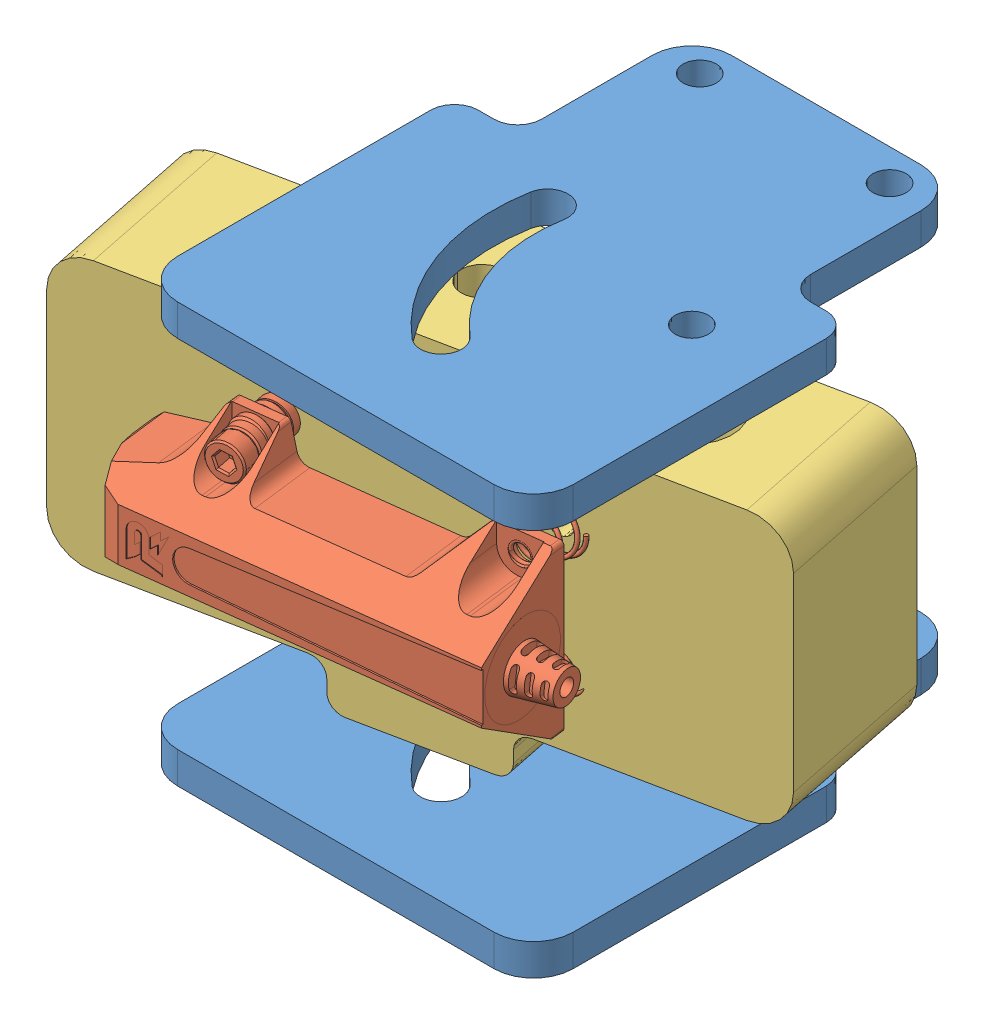
SolidWorks assembly 激光瞄准, configuration 默认. Lengths in mm.
Overall size (82.38 53 68.83).
4 component instances, 3 part files, 8 mates.
Components (placement in the parent):
- 21RM_飞镖.02.01.0048(激光瞄准旋转板)-1: 21RM_飞镖.02.01.0048(激光瞄准旋转板) [默认] at (10.6567 7.7365 63) size (50 4 62)
- 21RM_飞镖.02.01.0048(激光瞄准旋转板)-2: 21RM_飞镖.02.01.0048(激光瞄准旋转板) [默认] at (10.6567 -41.2635 63) size (50 4 62)
- 21RM_飞镖.02.01.0045(RoboMaster激光瞄准)-1: 21RM_飞镖.02.01.0045(RoboMaster激光瞄准) [默认] at (-50.7503 5.6982 100.4699) x (0 -1 0) z (-0.979741 0 0.200267) size (22.28 20.81 51.36)
- 21RM_飞镖.02.01.0046(激光瞄准固定板)-1: 21RM_飞镖.02.01.0046(激光瞄准固定板) [默认] at (-13.3901 -14.7635 57.7086) x (0 -1 0) z (-0.979741 0 0.200267) size (45 20 80)
Mates (geometry in assembly coordinates):
- 同心1: concentric aligned: cylinder of 21RM_飞镖.02.01.0048(激光瞄准旋转板)-1 through (10.6567 11.7365 63) axis (0 -1 0) radius 2.1; cylinder of 21RM_飞镖.02.01.0048(激光瞄准旋转板)-2 through (10.6567 -37.2635 63) axis (0 -1 0) radius 2.1
- 同心2: concentric aligned: circle of 21RM_飞镖.02.01.0045(RoboMaster激光瞄准)-1; cylinder of 21RM_飞镖.02.01.0046(激光瞄准固定板)-1 through (-24.0809 -22.7635 80.3074) axis (-0.200267 0 -0.979741) radius 1.6
- 同心5: concentric anti-aligned: cylinder of 21RM_飞镖.02.01.0045(RoboMaster激光瞄准)-1 through (-24.768 -6.7635 76.9458) axis (0.200267 0 0.979741) radius 1.25; cylinder of 21RM_飞镖.02.01.0046(激光瞄准固定板)-1 through (-24.0809 -6.7635 80.3074) axis (-0.200267 0 -0.979741) radius 1.6
- 重合3: coincident anti-aligned: plane of 21RM_飞镖.02.01.0045(RoboMaster激光瞄准)-1 through (-24.0809 -6.7635 80.3074) normal (-0.200267 0 -0.979741); plane of 21RM_飞镖.02.01.0046(激光瞄准固定板)-1 through (-9.3848 -14.7635 77.3034) normal (0.200267 0 0.979741)
- 平行4: parallel aligned: line of 21RM_飞镖.02.01.0048(激光瞄准旋转板)-1 through (-24.3433 11.7365 93) axis (1 0 0); line of 21RM_飞镖.02.01.0048(激光瞄准旋转板)-2 through (-24.3433 -37.2635 93) axis (1 0 0)
- 同心6: concentric anti-aligned: cylinder of 21RM_飞镖.02.01.0048(激光瞄准旋转板)-2 through (10.6567 -37.2635 63) axis (0 -1 0) radius 2.1; cylinder of 21RM_飞镖.02.01.0046(激光瞄准固定板)-1 through (10.6567 -37.2635 63) axis (0 1 0) radius 5.1
- 重合7: coincident anti-aligned: plane of 21RM_飞镖.02.01.0048(激光瞄准旋转板)-1 through (10.6567 7.7365 63) normal (0 -1 0); plane of 21RM_飞镖.02.01.0046(激光瞄准固定板)-1 through (-48.5744 7.7365 85.3141) normal (0 1 0)
- 重合8: coincident anti-aligned: plane of 21RM_飞镖.02.01.0048(激光瞄准旋转板)-2 through (10.6567 -37.2635 63) normal (0 1 0); plane of 21RM_飞镖.02.01.0046(激光瞄准固定板)-1 through (-48.5744 -37.2635 85.3141) normal (0 -1 0)
